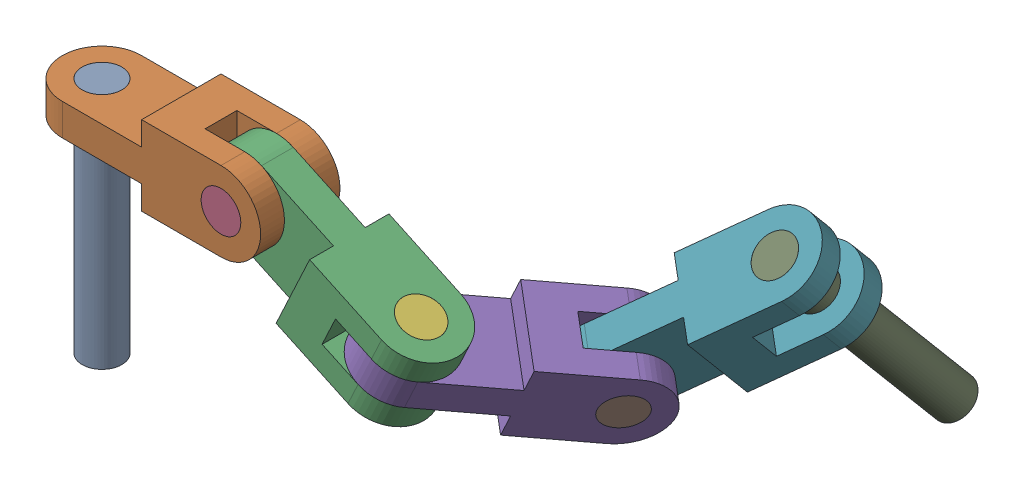
SolidWorks assembly Assemblage1, configuration Défaut. Lengths in mm.
Overall size (743.15 346.45 520.33).
9 component instances, 3 part files, 21 mates.
Components (placement in the parent):
- long_pin-1: long_pin [Default] at origin size (50 300 50)
- chain_link-1: chain_link [Default] at (100 -20 0) x (0 -1 0) z (0 0 1) size (100 300 100)
- chain_link-2: chain_link [Default] at (290.6308 -62.2618 0) x (0 0 1) z (0.422618 0.906308 0) size (100 300 100)
- short_pin-1: short_pin [Default] at (200 -20 50) x (1 0 0) z (0 -1 0) size (50 100 50)
- chain_link-3: chain_link [Default] at (433.2452 -128.764 -81.9152) x (0.422618 0.906308 0) z (-0.742404 0.346189 -0.573576) size (100 300 100)
- short_pin-2: short_pin [Default] at (402.3925 -59.2083 0) x (0.247049 -0.115201 0.962131) z (-0.871987 0.406614 0.272588) size (50 100 50)
- chain_link-4: chain_link [Default] at (551.0178 -99.1586 -216.4845) x (-0.742404 0.346189 -0.573576) z (0.126564 -0.768256 -0.627507) size (100 300 100)
- short_pin-3: short_pin [Default] at (448.1087 -135.695 -192.5092) x (0.658361 0.53556 -0.528901) z (-0.124085 0.770278 0.625519) size (50 100 50)
- long_pin-2: long_pin [Default] at (610.4785 -6.9001 -237.7632) x (0.412794 -0.534427 0.737556) z (-0.901988 -0.352379 0.249492) size (50 300 50)
Mates (geometry in assembly coordinates):
- Coaxiale3: concentric anti-aligned: cylinder of long_pin-1 through (0 -300 0) axis (0 1 0) radius 25; cylinder of chain_link-1 through (0 30 0) axis (0 -1 0) radius 25
- Coïncidente1: coincident aligned: plane of long_pin-1 through (0 0 0) normal (0 1 0); plane of chain_link-1 through (0 0 0) normal (0 1 0)
- Coaxiale4: concentric aligned: cylinder of chain_link-1 through (200 -20 -50) axis (0 0 1) radius 25; cylinder of chain_link-2 through (200 -20 -50) axis (0 0 1) radius 25
- Coïncidente2: coincident anti-aligned: plane of chain_link-1 through (250 30 20) normal (0 0 -1); plane of chain_link-2 through (200 -20 20) normal (0 0 1)
- Angle2: planar angle = 0.436332 rad aligned: plane of chain_link-1 through (100 30 50) normal (0 1 0); plane of chain_link-2 through (402.3925 -59.2083 0) normal (0.422618 0.906308 0)
- Coaxiale5: concentric aligned: cylinder of chain_link-1 through (200 -20 -50) axis (0 0 1) radius 25; cylinder of short_pin-1 through (200 -20 -50) axis (0 0 1) radius 25
- Coïncidente5: coincident aligned: plane of chain_link-1 through (200 -20 50) normal (0 0 1); plane of short_pin-1 through (200 -20 50) normal (0 0 1)
- Coaxiale6: concentric aligned: cylinder of chain_link-2 through (360.1306 -149.839 0) axis (0.422618 0.906308 0) radius 25; cylinder of chain_link-3 through (360.1306 -149.8391 0) axis (0.422618 0.906308 0) radius 25
- Coïncidente6: coincident anti-aligned: plane of chain_link-2 through (435.0293 -107.5284 -50) normal (-0.422618 -0.906308 0); plane of chain_link-3 through (389.7139 -86.3975 0) normal (0.422618 0.906308 0)
- Angle3: planar angle = 2.181662 rad anti-aligned: plane of chain_link-2 through (311.7617 -16.9464 -50) normal (0 0 -1); plane of chain_link-3 through (448.1087 -135.695 -192.5092) normal (-0.742404 0.346189 -0.573576)
- Coaxiale7: concentric aligned: cylinder of chain_link-2 through (360.1306 -149.839 0) axis (0.422618 0.906308 0) radius 25; cylinder of short_pin-2 through (360.1306 -149.839 0) axis (0.422618 0.906308 0) radius 25
- Coïncidente9: coincident aligned: plane of chain_link-2 through (402.3925 -59.2083 0) normal (0.422618 0.906308 0); plane of short_pin-2 through (402.3925 -59.2083 0) normal (0.422618 0.906308 0)
- Coaxiale8: concentric aligned: cylinder of chain_link-3 through (522.3491 -170.3139 -135.1516) axis (-0.742404 0.346189 -0.573576) radius 25; cylinder of chain_link-4 through (522.3491 -170.3139 -135.1516) axis (-0.742404 0.346189 -0.573576) radius 25
- Coïncidente10: coincident anti-aligned: plane of chain_link-3 through (475.2418 -203.5162 -216.2595) normal (0.742404 -0.346189 0.573576); plane of chain_link-4 through (470.3808 -146.0807 -175.3019) normal (-0.742404 0.346189 -0.573576)
- Angle4: planar angle = 2.268928 rad aligned: line of chain_link-3 through (491.5118 -100.7653 -175.3019) axis (-0.519837 0.242404 0.819152); line of chain_link-4 through (464.0526 -107.6679 -143.9266) axis (0.657889 0.538458 -0.526541)
- Coaxiale9: concentric aligned: cylinder of chain_link-3 through (522.3491 -170.3139 -135.1516) axis (-0.742404 0.346189 -0.573576) radius 25; cylinder of short_pin-3 through (522.3491 -170.3139 -135.1516) axis (-0.742404 0.346189 -0.573576) radius 25
- Coïncidente12: coincident aligned: plane of chain_link-3 through (448.1087 -135.695 -192.5092) normal (-0.742404 0.346189 -0.573576); plane of short_pin-3 through (448.1087 -135.695 -192.5092) normal (-0.742404 0.346189 -0.573576)
- Coaxiale10: concentric anti-aligned: cylinder of chain_link-4 through (520.8026 -303.1781 -300.5139) axis (-0.669872 -0.396871 0.627507) radius 25; cylinder of long_pin-2 through (319.841 -422.2395 -112.2618) axis (0.669872 0.396871 -0.627507) radius 25
- Coïncidente13: coincident aligned: plane of chain_link-4 through (520.8026 -303.1781 -300.5139) normal (0.669872 0.396871 -0.627507); plane of long_pin-2 through (520.8026 -303.1781 -300.5139) normal (0.669872 0.396871 -0.627507)
- Parallèle1: parallel aligned: plane of chain_link-1 through (200 -20 50) normal (0 0 1)
- Parallèle2: parallel anti-aligned: plane of chain_link-1 through (100 30 50) normal (-1 0 0)
